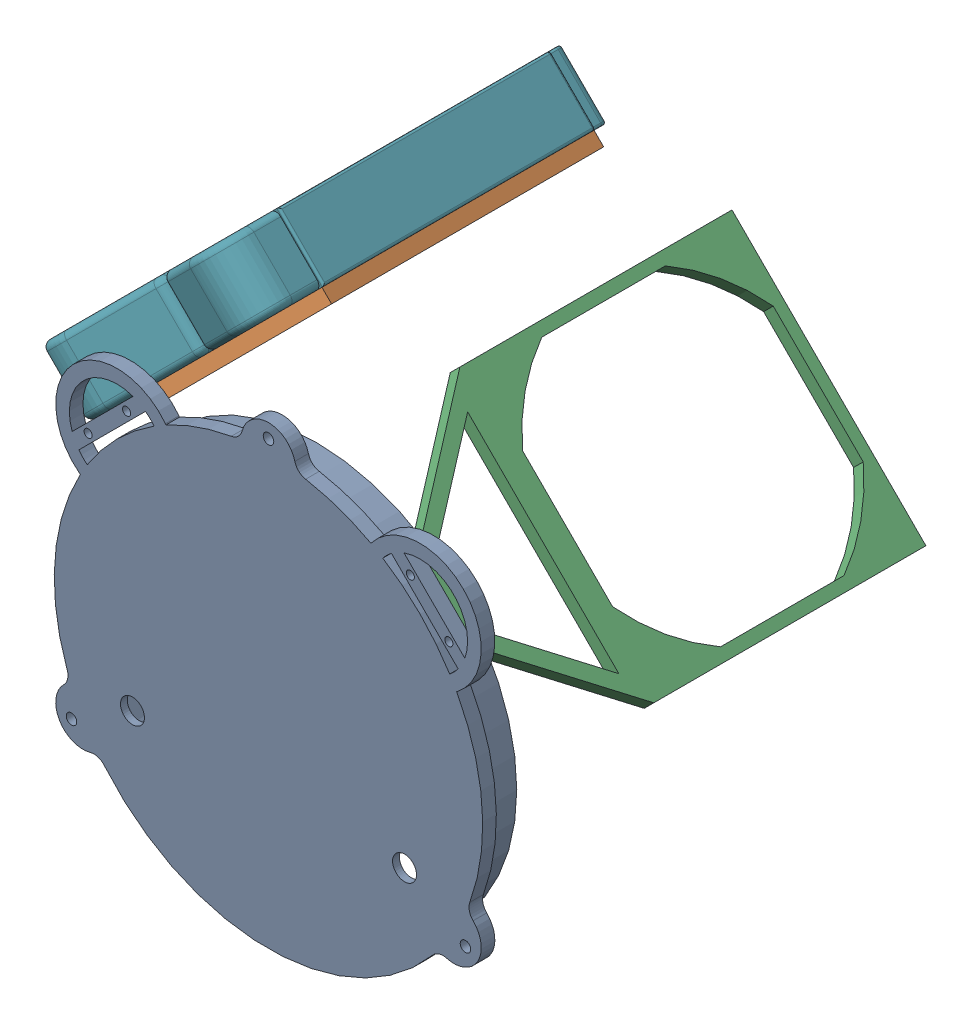
SolidWorks assembly Back endcap, configuration Default. Lengths in mm.
Overall size (266.76 243.8 192.15).
4 component instances, 3 part files, 8 mates.
Components (placement in the parent):
- back_endcap_glenair-1: back_endcap_glenair [Default] at (-35.8192 -4.608 22.4803) size (200.03 212.72 22.23)
- Radiator Mount-1: Radiator Mount [Default] at (-108.7838 68.3566 -91.8197) x (0.707107 0.707107 0) z (0 0 1) size (128 6.35 177.8)
- Radiator Mount-2: Radiator Mount [Default] at (37.1453 68.3566 -91.8197) x (0.707107 -0.707107 0) z (0 0 1) size (128 6.35 177.8)
- MCR120-1: MCR120 [Default] at (-124.0118 83.322 -163.3197) x (-0.707107 -0.707107 0) z (0 0 -1) size (128 30.16 162)
Mates (geometry in assembly coordinates):
- Concentric1: concentric aligned: circle of back_endcap_glenair-1; circle of Radiator Mount-1
- Concentric2: concentric aligned: circle of back_endcap_glenair-1; circle of Radiator Mount-1
- Coincident1: coincident anti-aligned: plane of back_endcap_glenair-1 through (-35.8192 -4.608 22.4803) normal (0 0 -1); plane of Radiator Mount-1 through (-122.2542 54.8862 22.4803) normal (0 0 1)
- Concentric3: concentric aligned: circle of back_endcap_glenair-1; circle of Radiator Mount-2
- Concentric4: concentric aligned: circle of back_endcap_glenair-1; circle of Radiator Mount-2
- Coincident2: coincident anti-aligned: plane of back_endcap_glenair-1 through (-35.8192 -4.608 22.4803) normal (0 0 -1); plane of Radiator Mount-2 through (23.675 81.827 22.4803) normal (0 0 1)
- Coincident3: coincident anti-aligned: line of Radiator Mount-1 through (-68.0191 118.1015 -155.3197) axis (-0.707107 -0.707107 0); line of MCR120-1 through (-69.9181 116.2025 -155.3197) axis (0.707107 0.707107 0)
- Coincident4: coincident anti-aligned: plane of Radiator Mount-1 through (-158.5288 27.5919 -28.3197) normal (-0.707107 0.707107 0); plane of MCR120-1 through (-68.1504 117.9703 -156.3197) normal (0.707107 -0.707107 0)
